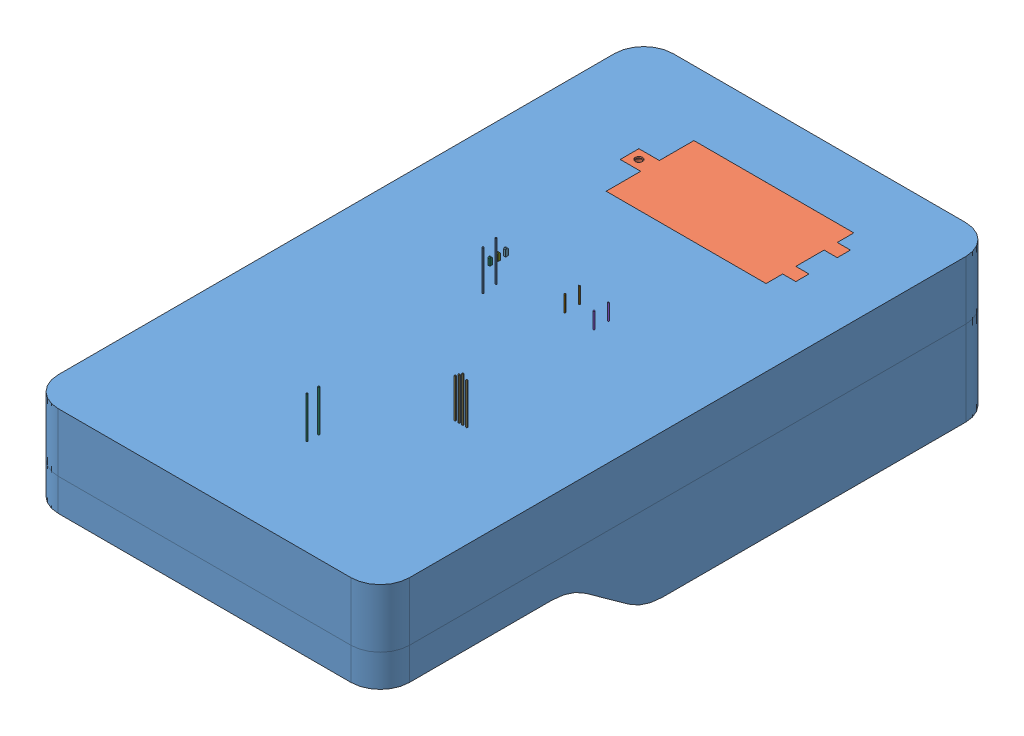
SolidWorks assembly final product with components, configuration Default. Lengths in mm.
Overall size (120 66.93 210).
87 component instances, 42 part files, 25 mates.
Components (placement in the parent):
- enclosure-1: enclosure [Default] at (135.8735 76.8205 148.6157) x (0 0 1) z (0 1 0) size (210 120 49.5)
- LCD-2: LCD [Default] at (92.8627 57.6205 104.3343) x (0 0 1) z (1 0 0) size (80 18.3 36)
  - pcbboard-1: pcbboard [Default] at origin size (80 4.2 36)
  - 16pin_header__-1: 16pin_header__ [Default] at (-32 0 -15.5) x (0 0 1) z (1 0 0) size (2.54 11.5 40.64)
  - lcd window-1: lcd window [Default] at (0 9 1.5) size (71.3 11.8 27.44)
  - backlight-1: backlight [Default] at (0 1.7 1.5) x (-1 0 0) z (0 0 -1) size (74.38 2.98 18)
  - conductor-1: conductor [Default] at (0 1.7 12.6) size (69.7 5.5 3)
  - conductor-2: conductor [Default] at (0 1.7 -9.6) size (69.7 5.5 3)
  - liquid crystal grabcad-1: liquid crystal grabcad [Default] at (0 7.9 1.5) size (68.5 2.2 25)
  - smt_resistor222-1: smt_resistor222 [Default] at (-32.75 0 -5.25) x (0 0 1) z (1 0 0) size (1.8 0.6 4)
  - smt_resistor222-2: smt_resistor222 [Default] at (-32.75 0 -2.75) x (0 0 1) z (1 0 0) size (1.8 0.6 4)
  - smt_resistor222-3: smt_resistor222 [Default] at (-32.75 0 -0.25) x (0 0 1) z (1 0 0) size (1.8 0.6 4)
  - smt_resistor222-4: smt_resistor222 [Default] at (-32.75 0 2.25) x (0 0 1) z (1 0 0) size (1.8 0.6 4)
  - smt_resistor222-5: smt_resistor222 [Default] at (-32.75 0 4.75) x (0 0 1) z (1 0 0) size (1.8 0.6 4)
  - smt_resistor222-6: smt_resistor222 [Default] at (-32.75 0 7.25) x (0 0 1) z (1 0 0) size (1.8 0.6 4)
  - smt_resistor101-1: smt_resistor101 [Default] at (30.25 0 6.1) x (0 0 -1) z (-1 0 0) size (1.8 0.6 5.2)
  - smt_resistor101-2: smt_resistor101 [Default] at (30.25 0 2.85) x (0 0 -1) z (-1 0 0) size (1.8 0.6 5.2)
- 1-1: 1 [Default] at (198.6784 86.409 89.3323) x (0 0 1) z (0 -1 0) size (109.98 65.02 42.54)
  - 1.step-1: 1.step [Default] at origin size (109.98 65.02 42.54)
    - Board.step-1: Board.step [Default] at origin size (109.98 65.02 0.41)
      - Open CASCADE STEP translator 6.8 2.1.1.step-1: Open CASCADE STEP translator 6.8 2.1.1.step [Default] at (0 0 -0.4115) size (109.98 65.02 0.41)
    - Free-Models.step-1: Free-Models.step [Default] at origin size (97.5 59.76 42.54)
      - JST_connector_1x8__P1.25mm_thru_hole_wafer_A2.step-1: JST_connector_1x8__P1.25mm_thru_hole_wafer_A2.step [Default] at (86.639 61.435 0) x (0 1 0) z (1 0 0) size (11.75 6.9 3.2)
        - pins.step-1: pins.step [Default] at origin size (9.25 5.4 0.75)
        - Open CASCADE STEP translator 6.8 2.2.40.2.step-1: Open CASCADE STEP translator 6.8 2.2.40.2.step [Default] at origin size (11.75 4.7 3.2)
      - regulator.step-1: regulator.step [Default] at (49.276 86.36 6) x (-1 0 0) z (0 1 0) size (10.43 0.01 1.4)
      - regulator-0.step-1: regulator-0.step [Default] at (49.276 86.36 6) x (-1 0 0) z (0 1 0) size (1.7 14 0.7)
      - regulator-1.step-1: regulator-1.step [Default] at (49.276 86.36 6) x (-1 0 0) z (0 1 0) size (1.7 14 0.7)
      - regulator-2.step-1: regulator-2.step [Default] at (49.276 86.36 6) x (-1 0 0) z (0 1 0) size (1.7 14 0.7)
      - regulator-3.step-1: regulator-3.step [Default] at (49.276 86.36 6) x (-1 0 0) z (0 1 0) size (10.4 9.42 0.03)
      - regulator-4.step-1: regulator-4.step [Default] at (49.276 86.36 6) x (-1 0 0) z (0 1 0) size (0.01 9.42 1.4)
      - regulator-5.step-1: regulator-5.step [Default] at (49.276 86.36 6) x (-1 0 0) z (0 1 0) size (0.01 9.42 1.4)
      - regulator-6.step-1: regulator-6.step [Default] at (49.276 86.36 6) x (-1 0 0) z (0 1 0) size (10.43 9.44 3.3)
      - regulator-7.step-1: regulator-7.step [Default] at (49.276 86.36 6) x (-1 0 0) z (0 1 0) size (10.4 15.75 1.4)
      - JST_B2B-XH-A_Through-hole_shrouded_header_top_entry_type.step-1: JST_B2B-XH-A_Through-hole_shrouded_header_top_entry_type.step [Default] at (50.419 96.491 0) x (-1 0 0) z (0 0 1) size (7.5 5.9 10.4)
      - B5B-XH-A.step-1: B5B-XH-A.step [Default] at (49.276 75.438 0) x (0 -1 0) z (-1 0 0) size (14.9 10.4 5.75)
      - B4B-XH-A.step-1: B4B-XH-A.step [Default] at (91.694 83.058 0) x (0 -1 0) z (-1 0 0) size (12.4 10.4 5.75)
      - Push_Button_Tactile.step-1: Push_Button_Tactile.step [Default] at (83.566 95.885 0) x (1 0 0) z (0 -1 0) size (7.66 3.5 6)
      - RDER71H105K2M1C03A.step-1: RDER71H105K2M1C03A.step [Default] at (50.8 52.705 2) x (1 0 0) z (0 -1 0) size (5.6 19.97 3.35)
      - RDER71H105K2M1C03A_1984339275.step-1: RDER71H105K2M1C03A_1984339275.step [Default] at (50.8 62.611 2) x (1 0 0) z (0 -1 0) size (5.51 19.97 3.33)
      - disccap.step-1: disccap.step [Default] at (59.0565 82.5638 4) x (1 0 0) z (0 0 -1) size (6.01 2.04 31)
      - 100uF.step-1: 100uF.step [Default] at (60.706 90.043 0) x (0 1 0) z (1 0 0) size (5.15 17.45 5.15)
      - 100uF.step-2: 100uF.step [Default] at (118.11 43.6559 0) x (1 0 0) z (0 -1 0) size (5.15 17.45 5.15)
      - 100uF.step-3: 100uF.step [Default] at (96.866 95.977 0) x (0 1 0) z (1 0 0) size (5.15 17.45 5.15)
      - CA_GRB_LED_5mm.step-1: CA_GRB_LED_5mm.step [Default] at (103.93 47.4375 0) x (0 -1 0) z (-1 0 0) size (5.12 34.2 5.5)
      - 100uF.step-4: 100uF.step [Default] at (59.563 47.4658 0) x (1 0 0) z (0 -1 0) size (5.15 17.45 5.15)
      - axial_resistor_6mm.step-1: axial_resistor_6mm.step [Default] at (110.236 74.236 2) x (1 0 0) z (0 -1 0) size (10.3 5.14 2.15)
      - axial_resistor_6mm.step-2: axial_resistor_6mm.step [Default] at (110.49 67.31 2) x (1 0 0) z (0 -1 0) size (10.3 5.14 2.15)
      - axial_resistor_6mm.step-3: axial_resistor_6mm.step [Default] at (110.49 83.439 2) x (1 0 0) z (0 -1 0) size (10.3 5.14 2.15)
      - axial_resistor_6mm.step-4: axial_resistor_6mm.step [Default] at (92.456 47.244 2) x (1 0 0) z (0 -1 0) size (10.3 5.14 2.15)
      - axial_resistor_6mm.step-5: axial_resistor_6mm.step [Default] at (71.696 93.218 2) x (0 1 0) z (1 0 0) size (10.3 5.14 2.15)
      - axial_resistor_6mm.step-6: axial_resistor_6mm.step [Default] at (110.617 92.837 2) x (1 0 0) z (0 -1 0) size (10.3 5.14 2.15)
      - axial_resistor_6mm.step-7: axial_resistor_6mm.step [Default] at (120.777 84.269 2) x (1 0 0) z (0 -1 0) size (10.3 5.14 2.15)
      - axial_resistor_6mm.step-8: axial_resistor_6mm.step [Default] at (87.376 55.948 2) x (1 0 0) z (0 -1 0) size (10.3 5.14 2.15)
      - axial_resistor_6mm.step-9: axial_resistor_6mm.step [Default] at (110.617 57.472 2) x (1 0 0) z (0 -1 0) size (10.3 5.14 2.15)
      - axial_resistor_6mm.step-10: axial_resistor_6mm.step [Default] at (92.329 43.502 2) x (1 0 0) z (0 -1 0) size (10.3 5.14 2.15)
      - axial_resistor_6mm.step-11: axial_resistor_6mm.step [Default] at (82.296 43.121 2) x (1 0 0) z (0 -1 0) size (10.3 5.14 2.15)
      - crystal_oscillator.step-1: crystal_oscillator.step [Default] at (58.42 60.071 0) x (0 1 0) z (1 0 0) size (11.05 6.5 4.65)
      - Part7.step-1: Part7.step [Default] at (133.35 68.602 9) x (1 0 0) z (0 -1 0) size (5 35.01 3.6)
      - ATMEGA328p.step-1: ATMEGA328p.step [Default] at (67.472 83.312 0) x (1 0 0) z (0 0 1) size (8.13 35.4 6.99)
      - LED_GREEN_5MM.step-1: LED_GREEN_5MM.step [Default] at (63.758 97.838 9) x (0 -1 0) z (0 0 -1) size (6 5.5 14)
      - LED_GREEN_5MM.step-2: LED_GREEN_5MM.step [Default] at (138.097 76.585 9) x (1 0 0) z (0 0 -1) size (6 5.5 14)
      - LED_GREEN_5MM.step-3: LED_GREEN_5MM.step [Default] at (123.103 67.993 9) x (0 1 0) z (0 0 -1) size (6 5.5 14)
      - LED_GREEN_5MM.step-4: LED_GREEN_5MM.step [Default] at (138.557 60.071 9) x (-1 0 0) z (0 0 -1) size (6 5.5 14)
- Part1^final product with components-1: Part1^final product with components [Default] at (198.6784 86.8205 89.3323) x (0 0 -1) z (0 1 0) (virtual)
- BATTARY HOLDER-1: BATTARY HOLDER [По умолчанию] at (134.5657 73.8205 84.7159) x (-1 0 0) z (0 0 -1) size (54.61 22.5 29.97)
- 9v battery.stp-1: 9v battery.stp [Default] at (62.375 -5.5898 137.2884) x (-1 0 0) z (0 0 -1) size (47.88 17.14 26.03)
- holder cap-2: holder cap [Default] at (145.0019 96.819 72.1871) x (1 0 0) z (0 0 -1) size (66.11 5 29.97)
- !keypad-3: !keypad [Default] at (155.142 57.16 120.7693) x (0 0 1) z (0 -1 0) size (65.28 67.82 9.4)
  - plastic_base-1: plastic_base [Default] at (-16.436 8.6289 2.8107) size (65.28 63.88 6.53)
  - pcb-1: pcb [Default] at (-16.436 6.6629 4.2077) x (-1 0 0) z (0 0 -1) size (62.74 67.82 1.55)
  - key-1: key [Default] at (-37.6831 27.9075 9.3385) size (8.31 7.36 2.74)
  - key-2: key [Default] at (-37.6831 14.9535 9.3385) size (8.31 7.36 2.74)
  - key-3: key [Default] at (-37.6831 1.9995 9.3385) size (8.31 7.36 2.74)
  - key-4: key [Default] at (-37.6831 -10.9545 9.3385) size (8.31 7.36 2.74)
  - key-5: key [Default] at (-23.4591 27.9075 9.3385) size (8.31 7.36 2.74)
  - key-6: key [Default] at (-23.4591 14.9535 9.3385) size (8.31 7.36 2.74)
  - key-7: key [Default] at (-23.4591 1.9995 9.3385) size (8.31 7.36 2.74)
  - key-8: key [Default] at (-23.4591 -10.9545 9.3385) size (8.31 7.36 2.74)
  - key-9: key [Default] at (-9.2351 27.9075 9.3385) size (8.31 7.36 2.74)
  - key-10: key [Default] at (-9.2351 14.9535 9.3385) size (8.31 7.36 2.74)
  - key-11: key [Default] at (-9.2351 1.9995 9.3385) size (8.31 7.36 2.74)
  - key-12: key [Default] at (-9.2351 -10.9545 9.3385) size (8.31 7.36 2.74)
  - key-13: key [Default] at (4.9889 27.9075 9.3385) size (8.31 7.36 2.74)
  - key-14: key [Default] at (4.9889 14.9535 9.3385) size (8.31 7.36 2.74)
  - key-15: key [Default] at (4.9889 1.9995 9.3385) size (8.31 7.36 2.74)
  - key-16: key [Default] at (4.9889 -10.9545 9.3385) size (8.31 7.36 2.74)
Mates (geometry in assembly coordinates):
- Coincident11: coincident anti-aligned: plane of enclosure-1 through (135.8735 55.9205 148.6157) normal (0 1 0); plane of LCD-2/pcbboard-1 through (92.8627 55.9205 104.3343) normal (0 -1 0)
- Coincident12: coincident anti-aligned: plane of enclosure-1 through (110.8627 55.9205 144.3343) normal (0 0 -1); plane of LCD-2/pcbboard-1 through (74.8627 55.9205 144.3343) normal (0 0 1)
- Coincident13: coincident anti-aligned: plane of enclosure-1 through (110.8627 55.9205 64.3343) normal (-1 0 0); plane of LCD-2/pcbboard-1 through (110.8627 55.9205 64.3343) normal (1 0 0)
- Coincident14: coincident anti-aligned: plane of enclosure-1 through (99.4514 86.8205 131.5793) normal (0 -1 0); plane of 1-1/1.step-1/Board.step-1/Open CASCADE STEP translator 6.8 2.1.1.step-1 through (160.4514 86.8205 237.5413) normal (0 1 0)
- Concentric1: concentric anti-aligned: cylinder of enclosure-1 through (99.4514 87.0745 233.5593) axis (0 -1 0) radius 1; cylinder of 1-1/1.step-1/Board.step-1/Open CASCADE STEP translator 6.8 2.1.1.step-1 through (99.4514 86.8205 233.5593) axis (0 1 0) radius 1
- Parallel2: parallel anti-aligned: cylinder of enclosure-1 through (156.4727 87.0745 131.5793) axis (0 -1 0) radius 1; cylinder of 1-1/1.step-1/Board.step-1/Open CASCADE STEP translator 6.8 2.1.1.step-1 through (156.4514 86.8205 131.5593) axis (0 1 0) radius 1
- InPlace1: in place: plane of 1-1/1.step-1/Board.step-1/Open CASCADE STEP translator 6.8 2.1.1.step-1 through (160.4514 86.8205 237.5413) normal (0 1 0); plane of ? through (0 86.8205 0) normal (0 1 0); moOrthogonalPlaneRef_w of 1-1/1.step-1/Board.step-1/Open CASCADE STEP translator 6.8 2.1.1.step-1 through (160.4514 86.8205 237.5413) normal (0 1 0); plane of ? through (0 86.8205 0) normal (0 0 -1); plane of 1-1/1.step-1/Board.step-1/Open CASCADE STEP translator 6.8 2.1.1.step-1 through (160.4514 86.8205 237.5413) normal (0 1 0); plane of ? through (0 86.8205 0) normal (1 0 0); plane of 1-1/1.step-1/Board.step-1/Open CASCADE STEP translator 6.8 2.1.1.step-1 through (160.4514 86.8205 237.5413) normal (0 1 0); unknown of Part1^final product with components-1
- Coincident15: coincident aligned: plane of 1-1/1.step-1/Board.step-1/Open CASCADE STEP translator 6.8 2.1.1.step-1; plane of Part1^final product with components-1
- Coincident16: coincident aligned: moOrthogonalPlaneRef_w of 1-1/1.step-1/Board.step-1/Open CASCADE STEP translator 6.8 2.1.1.step-1 through (198.6784 86.8205 89.3323) normal (-1 0 0); plane of Part1^Assem2-1 through (198.6784 86.8205 89.3323) normal (-1 0 0)
- Coincident17: coincident anti-aligned: moOrthogonalPlaneRef_w of 1-1/1.step-1/Board.step-1/Open CASCADE STEP translator 6.8 2.1.1.step-1 through (198.6784 86.8205 89.3323) normal (0 0 1); plane of Part1^Assem2-1 through (198.6784 86.8205 89.3323) normal (0 0 -1)
- Coincident18: coincident anti-aligned: plane of enclosure-1 through (161.8707 47.8195 69.7309) normal (-1 0 0); plane of BATTARY HOLDER-1 through (161.8707 76.3205 99.7009) normal (1 0 0)
- Coincident19: coincident anti-aligned: plane of enclosure-1 through (107.2607 47.8195 69.7309) normal (1 0 0); plane of BATTARY HOLDER-1 through (107.2607 76.3205 99.7009) normal (-1 0 0)
- Coincident20: coincident anti-aligned: plane of enclosure-1 through (161.8707 47.8195 69.7309) normal (0 0 1); plane of BATTARY HOLDER-1 through (161.8707 76.3205 69.7309) normal (0 0 -1)
- Coincident22: coincident aligned: plane of enclosure-1 through (135.8735 73.8205 148.6157) normal (0 -1 0); plane of BATTARY HOLDER-1 through (134.5657 73.8205 84.7159) normal (0 -1 0)
- Coincident30: coincident anti-aligned: plane of BATTARY HOLDER-1 through (159.2607 83.3205 94.2159) normal (-1 0 0); plane of 9v battery.stp-1 through (159.2607 77.49 96.2094) normal (1 0 0)
- Parallel4: parallel anti-aligned: cylinder of BATTARY HOLDER-1 through (114.2607 85.3005 91.0659) axis (-1 0 0) radius 2; cylinder of 9v battery.stp-1 through (115.8267 85.3005 91.0659) axis (1 0 0) radius 2.8575
- Parallel5: parallel anti-aligned: cylinder of BATTARY HOLDER-1 through (114.2607 85.3005 91.0659) axis (-1 0 0) radius 3; cylinder of 9v battery.stp-1 through (115.8267 85.3005 91.0659) axis (1 0 0) radius 2.8575
- Parallel11: parallel anti-aligned: plane of BATTARY HOLDER-1 through (110.2607 85.3005 78.3659) normal (1 0 0); plane of 9v battery.stp-1 through (111.6357 88.8946 78.3659) normal (-1 0 0)
- Concentric10: concentric aligned: circle of BATTARY HOLDER-1; circle of 9v battery.stp-1
- Coincident31: coincident anti-aligned: plane of enclosure-1 through (161.8707 47.8195 99.7009) normal (0 0 -1); plane of holder cap-2 through (145.0019 93.819 99.7009) normal (0 0 1)
- Coincident32: coincident anti-aligned: plane of enclosure-1 through (135.8735 94.7605 148.6157) normal (0 1 0); plane of holder cap-2 through (100.22 94.7605 99.7019) normal (0 -1 0)
- Coincident33: coincident anti-aligned: plane of enclosure-1 through (166.3707 94.7605 89.5409) normal (-1 0 0); plane of holder cap-2 through (166.3707 93.819 72.1871) normal (1 0 0)
- Coincident34: coincident anti-aligned: plane of enclosure-1 through (179.4227 51.2505 74.2343) normal (0 1 0); plane of !keypad-3/plastic_base-1 through (217.6962 51.2505 104.3333) normal (0 -1 0)
- Concentric11: concentric aligned: cylinder of enclosure-1 through (117.1127 51.2505 74.2343) axis (0 1 0) radius 2.54; cylinder of !keypad-3/plastic_base-1 through (117.1127 51.2505 74.2343) axis (0 1 0) radius 2.54
- Parallel12: parallel anti-aligned: plane of enclosure-1 through (117.1127 51.2505 136.9743) normal (0 0 -1); plane of !keypad-3/plastic_base-1 through (217.6962 51.2505 136.9723) normal (0 0 1)
